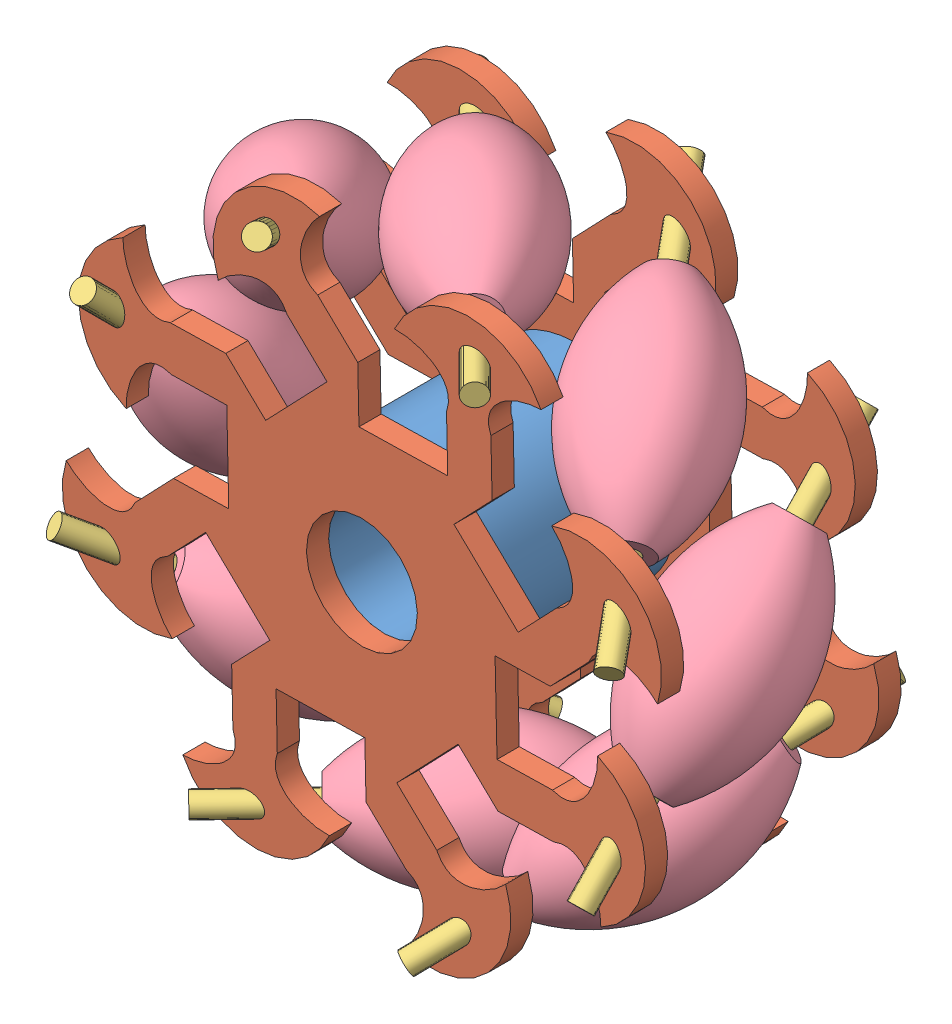
SolidWorks assembly full wheel, configuration Default. Lengths in mm.
Overall size (38.38 38.37 18.55).
27 component instances, 4 part files, 16 mates.
Components (placement in the parent):
- wheel joint-1: wheel joint [Default] at (-4.3261 7.2325 9.2411) size (9 9 8.67)
- wheel rim-1: wheel rim [Default] at (-4.3261 7.2325 18.9111) x (0.999757 0.022047 0) z (0 0 1) size (27.13 27.15 10.6)
- wheel rim-2: wheel rim [Default] at (-4.3261 7.2325 8.2413) x (-0.691345 -0.722525 0) z (0 0 -1) size (27.13 27.15 10.6)
- sub_assem-1: sub_assem [Default] at (-19.3508 25.979 6.7984) x (0.85787 -0.42869 -0.283345) z (-0.158368 -0.74512 0.647855) size (6.14 18.5 6.14)
  - rod-1: rod [Default] at (8.8671 2.7878 11.5459) size (1 18.5 1)
  - roller-1: roller [Default] at (8.8671 2.7878 11.5459) size (6.14 10 6.14)
- sub_assem-2: sub_assem [Default] at (-12.9176 29.6598 18.0212) x (0.706935 0.01559 -0.707107) z (0.022047 -0.999757 0) size (6.14 18.5 6.14)
  - rod-1: rod [Default] at (8.8671 2.7878 11.5459) size (1 18.5 1)
  - roller-1: roller [Default] at (8.8671 2.7878 11.5459) size (6.14 10 6.14)
- sub_assem-3: sub_assem [Default] at (18.1013 15.824 18.0212) x (0.01559 -0.706935 -0.707107) z (-0.999757 -0.022047 0) size (6.14 18.5 6.14)
  - rod-1: rod [Default] at (8.8671 2.7878 11.5459) size (1 18.5 1)
  - roller-1: roller [Default] at (8.8671 2.7878 11.5459) size (6.14 10 6.14)
- sub_assem-4: sub_assem [Default] at (4.2654 -15.1949 18.0212) x (-0.706935 -0.01559 -0.707107) z (-0.022047 0.999757 0) size (6.14 18.5 6.14)
  - rod-1: rod [Default] at (8.8671 2.7878 11.5459) size (1 18.5 1)
  - roller-1: roller [Default] at (8.8671 2.7878 11.5459) size (6.14 10 6.14)
- sub_assem-5: sub_assem [Default] at (-26.7534 -1.359 18.0212) x (-0.01559 0.706935 -0.707107) z (0.999757 0.022047 0) size (6.14 18.5 6.14)
  - rod-1: rod [Default] at (8.8671 2.7878 11.5459) size (1 18.5 1)
  - roller-1: roller [Default] at (8.8671 2.7878 11.5459) size (6.14 10 6.14)
- sub_assem-6: sub_assem [Default] at (14.4204 22.2572 6.7984) x (-0.42869 -0.85787 -0.283345) z (-0.74512 0.158368 0.647855) size (6.14 18.5 6.14)
  - rod-1: rod [Default] at (8.8671 2.7878 11.5459) size (1 18.5 1)
  - roller-1: roller [Default] at (8.8671 2.7878 11.5459) size (6.14 10 6.14)
- sub_assem-7: sub_assem [Default] at (10.6986 -11.514 6.7984) x (-0.85787 0.42869 -0.283345) z (0.158368 0.74512 0.647855) size (6.14 18.5 6.14)
  - rod-1: rod [Default] at (8.8671 2.7878 11.5459) size (1 18.5 1)
  - roller-1: roller [Default] at (8.8671 2.7878 11.5459) size (6.14 10 6.14)
- sub_assem-8: sub_assem [Default] at (-23.0726 -7.7922 6.7984) x (0.42869 0.85787 -0.283345) z (0.74512 -0.158368 0.647855) size (6.14 18.5 6.14)
  - rod-1: rod [Default] at (8.8671 2.7878 11.5459) size (1 18.5 1)
  - roller-1: roller [Default] at (8.8671 2.7878 11.5459) size (6.14 10 6.14)
Mates (geometry in assembly coordinates):
- Concentric1: concentric anti-aligned: cylinder of wheel joint-1 through (-4.3261 7.2325 17.9111) axis (0 0 -1) radius 2.5; cylinder of wheel rim-1 through (-4.3261 7.2325 17.9111) axis (0 0 1) radius 2.5
- Coincident1: coincident anti-aligned: plane of wheel joint-1 through (-4.3261 7.2325 17.9111) normal (0 0 1); plane of wheel rim-1 through (-4.3261 7.2325 17.9111) normal (0 0 -1)
- Concentric2: concentric aligned: cylinder of wheel joint-1 through (-4.3261 7.2325 17.9111) axis (0 0 -1) radius 2.5; cylinder of wheel rim-2 through (-4.3261 7.2325 9.2413) axis (0 0 -1) radius 2.5
- Concentric3: concentric aligned: cylinder of wheel rim-1 through (-7.5284 18.2299 10.6171) axis (-0.706935 -0.01559 -0.707107) radius 0.5; cylinder of wheel rim-2 through (2.8533 18.4589 21.0013) axis (-0.706935 -0.01559 -0.707107) radius 0.5
- Parallel1: parallel anti-aligned: plane of wheel joint-1 through (-4.3261 7.2325 9.2411) normal (0 0 -1); plane of wheel rim-2 through (-4.3261 7.2325 9.2413) normal (0 0 1)
- Concentric5: concentric anti-aligned: cylinder of wheel rim-1 through (-17.4544 9.5176 6.151) axis (0.488855 0.510902 0.707107) radius 0.5; cylinder of sub_assem-1/rod-1 through (-7.6878 19.7248 20.2781) axis (-0.488855 -0.510902 -0.707107) radius 0.5
- Concentric6: concentric aligned: cylinder of wheel rim-1 through (-7.5284 18.2299 10.6171) axis (-0.706935 -0.01559 -0.707107) radius 0.5; cylinder of sub_assem-2/rod-1 through (2.1154 18.4426 20.2632) axis (-0.706935 -0.01559 -0.707107) radius 0.5
- Parallel2: parallel anti-aligned: plane of wheel rim-1 through (-4.3261 7.2325 18.9111) normal (-0.022047 0.999757 0); plane of sub_assem-2 through (-12.9176 29.6598 18.0212) normal (0.022047 -0.999757 0)
- Lock1: lock: unknown of ?; unknown of ?
- Lock2: lock: unknown of ?; unknown of ?
- Lock3: lock: unknown of ?; unknown of ?
- Lock4: lock: unknown of ?; unknown of ?
- Lock5: lock: unknown of ?; unknown of ?
- Lock6: lock: unknown of ?; unknown of ?
- Lock7: lock: unknown of ?; unknown of ?
- Lock8: lock: unknown of ?; unknown of wheel joint-1
